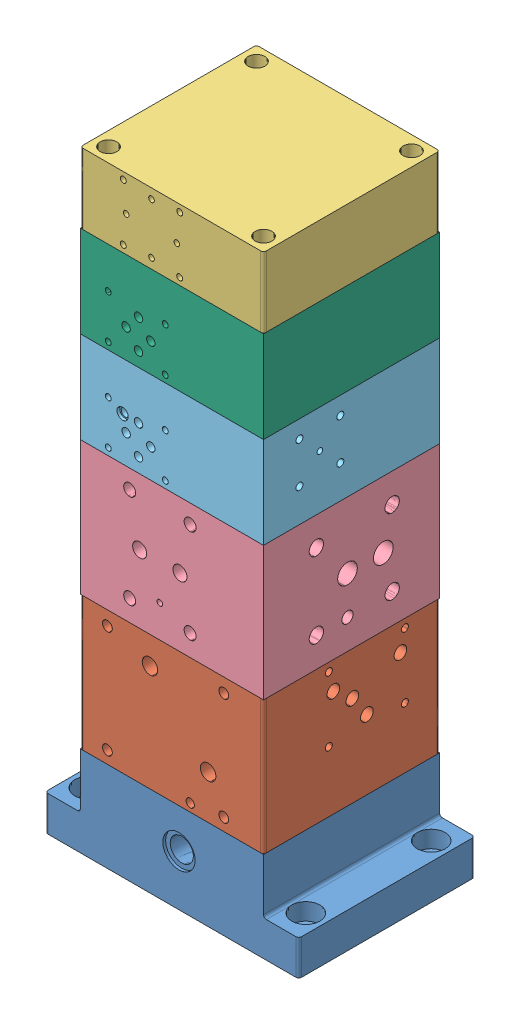
SolidWorks assembly 集成回路, configuration Default. Lengths in mm.
Overall size (180 434 125).
6 component instances, 6 part files, 15 mates.
Components (placement in the parent):
- 底板-1: 底板 [Default] at origin size (180 64 125)
- 方向调速块-1: 方向调速块 [Default] at (0 65 0) size (130 95 125)
- 顶盖-1: 顶盖 [Default] at (0 384 0) size (130 50 125)
- 压力块-1: 压力块 [默认] at (0 206.5 0) size (130 95 125)
- 夹紧块-1: 夹紧块 [默认] at (0 254 0) x (-1 0 0) z (0 0 -1) size (130 65 125)
- 定位块-3: 定位块 [默认] at (0 319 0) x (-1 0 0) z (0 0 -1) size (130 65 125)
Mates (geometry in assembly coordinates):
- 重合1: coincident aligned: plane of 底板-1 through (-90 25 62.5) normal (0 0 1); plane of 方向调速块-1 through (-65 165 62.5) normal (0 0 1)
- 重合2: coincident aligned: plane of 底板-1 through (65 64 -62.5) normal (1 0 0); plane of 方向调速块-1 through (65 165 -62.5) normal (1 0 0)
- 重合3: coincident aligned: plane of 方向调速块-1 through (65 165 -62.5) normal (1 0 0); plane of 顶盖-1 through (65 519.8526 -62.5) normal (1 0 0)
- 重合4: coincident aligned: plane of 方向调速块-1 through (-65 165 62.5) normal (0 0 1); plane of 顶盖-1 through (-65 519.8526 62.5) normal (0 0 1)
- 重合5: coincident anti-aligned: plane of 底板-1 through (0 64 0) normal (0 1 0); plane of 方向调速块-1 through (63 64 60.5) normal (0 -1 0)
- 重合6: coincident aligned: plane of 方向调速块-1 through (-65 165 62.5) normal (0 0 1); plane of 压力块-1 through (-65 254 62.5) normal (0 0 1)
- 重合7: coincident aligned: plane of 方向调速块-1 through (65 165 -62.5) normal (1 0 0); plane of 压力块-1 through (65 254 62.5) normal (1 0 0)
- 重合8: coincident aligned: plane of 压力块-1 through (-65 254 62.5) normal (-1 0 0); plane of 夹紧块-1 through (-65 319 -62.5) normal (-1 0 0)
- 重合9: coincident aligned: plane of 压力块-1 through (-65 254 62.5) normal (0 0 1); plane of 夹紧块-1 through (65 319 62.5) normal (0 0 1)
- 重合10: coincident anti-aligned: plane of 方向调速块-1 through (-65 159 -62.5) normal (0 1 0); plane of 压力块-1 through (0 159 0) normal (0 -1 0)
- 重合11: coincident anti-aligned: plane of 压力块-1 through (0 254 0) normal (0 1 0); plane of 夹紧块-1 through (0 254 0) normal (0 -1 0)
- 重合12: coincident aligned: plane of 夹紧块-1 through (65 319 -62.5) normal (1 0 0); plane of 定位块-3 through (65 384 -62.5) normal (1 0 0)
- 重合13: coincident aligned: plane of 夹紧块-1 through (65 319 62.5) normal (0 0 1); plane of 定位块-3 through (65 384 62.5) normal (0 0 1)
- 重合14: coincident anti-aligned: plane of 夹紧块-1 through (0 319 0) normal (0 1 0); plane of 定位块-3 through (0 319 0) normal (0 -1 0)
- 重合15: coincident anti-aligned: plane of 顶盖-1 through (0 384 0) normal (0 -1 0); plane of 定位块-3 through (0 384 0) normal (0 1 0)
